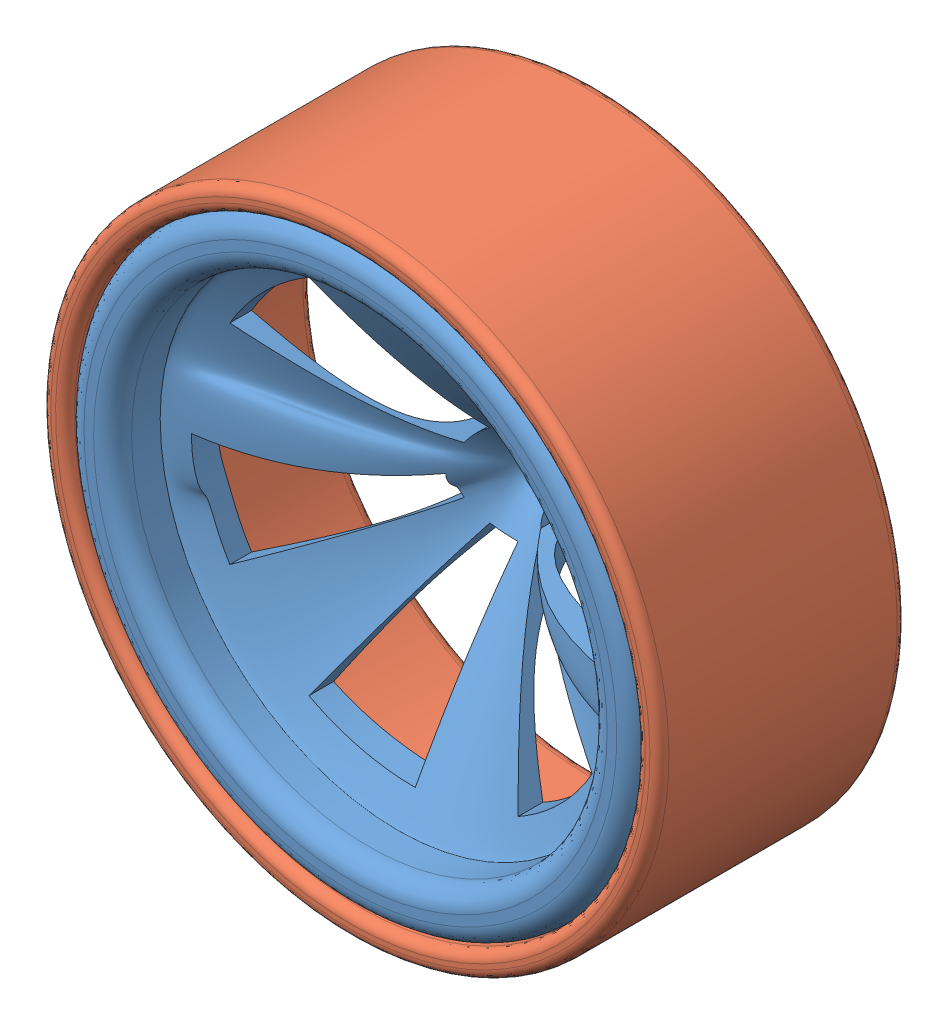
SolidWorks assembly 整个车轮, configuration 默认. Lengths in mm.
Overall size (84.94 84.94 26).
2 component instances, 2 part files, 2 mates.
Components (placement in the parent):
- 轮胎-1: 轮胎 [默认] at (-2.4455 0.4479 54.1725) size (63.39 63.18 21.57)
- 轮胎外-1: 轮胎外 [默认] at (-2.4455 0.4479 48.1725) x (0.923728 0.383049 0) z (0.383049 -0.923728 0) size (65 26 65)
Mates (geometry in assembly coordinates):
- 相切2: tangent: face of 轮胎-1; cylinder of 轮胎外-1 through (-2.4455 0.4479 74.1725) axis (0 0 -1) radius 30
- 重合1: coincident aligned: plane of 轮胎-1 through (-32.4455 0.4479 74.1725) normal (0 0 1); plane of 轮胎外-1 through (-2.4455 0.4479 74.1725) normal (0 0 1)
